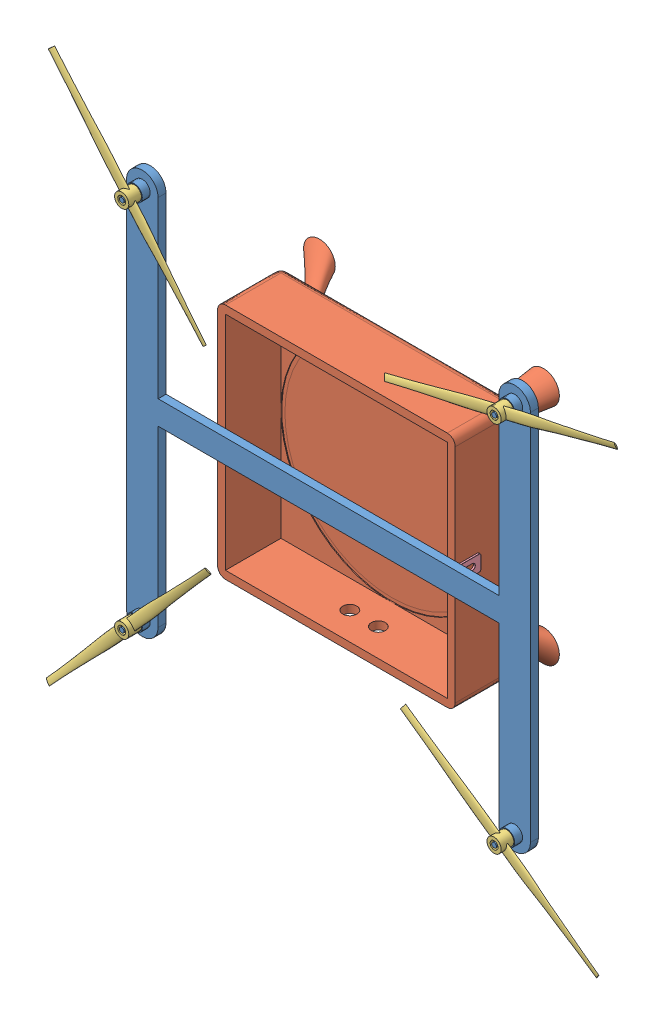
SolidWorks assembly Assembly2, configuration Default. Lengths in mm.
Overall size (362.76 353.79 78).
8 component instances, 4 part files, 19 mates.
Components (placement in the parent):
- arm2-1: arm2 [Default] at (-180.7832 0 40) size (255 255 18)
- body2-1: body2 [Default] at (-180.7832 0 0) x (0 1 0) z (0 0 1) size (161.43 161.43 60)
- blade-1: blade [Default] at (-63.2832 -117.5 50) x (-0.574324 -0.818628 0) z (0 0 1) size (9 150.02 8)
- blade-2: blade [Default] at (-298.2832 -117.5 50) x (0.739775 -0.672854 0) z (0 0 1) size (9 150.02 8)
- blade-3: blade [Default] at (-63.2832 117.5 50) x (0.235026 -0.971989 0) z (0 0 1) size (9 150.02 8)
- blade-4: blade [Default] at (-298.2832 117.5 50) x (0.764856 0.644202 0) z (0 0 1) size (9 150.02 8)
- angle_bracket_15x15x10-3: angle_bracket_15x15x10 [Default] at (-255.7832 -5 40) x (0 0 -1) z (0 1 0) size (15 15 10)
- angle_bracket_15x15x10-4: angle_bracket_15x15x10 [Default] at (-105.7832 5 40) x (0 0 -1) z (0 -1 0) size (15 15 10)
Mates (geometry in assembly coordinates):
- Concentric1: concentric aligned: cylinder of arm2-1 through (-298.2832 117.5 58) axis (0 0 -1) radius 1.5; cylinder of blade-4 through (-298.2832 117.5 58) axis (0 0 -1) radius 2.5
- Coincident5: coincident anti-aligned: plane of arm2-1 through (-298.2832 117.5 50) normal (0 0 1); plane of blade-4 through (-298.2832 117.5 50) normal (0 0 -1)
- Concentric2: concentric aligned: cylinder of arm2-1 through (-63.2832 117.5 58) axis (0 0 -1) radius 1.5; cylinder of blade-3 through (-63.2832 117.5 58) axis (0 0 -1) radius 2.5
- Coincident6: coincident anti-aligned: plane of arm2-1 through (-63.2832 117.5 50) normal (0 0 1); plane of blade-3 through (-63.2832 117.5 50) normal (0 0 -1)
- Concentric3: concentric aligned: cylinder of arm2-1 through (-298.2832 -117.5 58) axis (0 0 -1) radius 1.5; cylinder of blade-2 through (-298.2832 -117.5 58) axis (0 0 -1) radius 2.5
- Coincident7: coincident anti-aligned: plane of arm2-1 through (-298.2832 -117.5 50) normal (0 0 1); plane of blade-2 through (-298.2832 -117.5 50) normal (0 0 -1)
- Concentric5: concentric aligned: cylinder of arm2-1 through (-63.2832 -117.5 58) axis (0 0 -1) radius 1.5; cylinder of blade-1 through (-63.2832 -117.5 58) axis (0 0 -1) radius 2.5
- Coincident8: coincident anti-aligned: plane of arm2-1 through (-63.2832 -117.5 50) normal (0 0 1); plane of blade-1 through (-63.2832 -117.5 50) normal (0 0 -1)
- Coincident24: coincident: point of arm2-1; point of body2-1
- Coincident42: coincident anti-aligned: plane of body2-1 through (-180.7832 0 0) normal (0 0 -1)
- Coincident43: coincident: line of body2-1 through (-258.9452 0 0) axis (1 0 0)
- Parallel11: parallel aligned: line of arm2-1 through (-298.2832 0 40) axis (1 0 0); line of body2-1 through (-258.9452 0 0) axis (1 0 0)
- Coincident46: coincident anti-aligned: plane of arm2-1 through (-298.2832 117.5 40) normal (0 0 -1); plane of body2-1 through (-180.7832 0 40) normal (0 0 1)
- Coincident47: coincident anti-aligned: plane of body2-1 through (-255.7832 -75 40) normal (-1 0 0); plane of angle_bracket_15x15x10-3 through (-255.7832 5 25) normal (1 0 0)
- Coincident48: coincident anti-aligned: plane of arm2-1 through (-298.2832 117.5 40) normal (0 0 -1); plane of angle_bracket_15x15x10-3 through (-255.7832 5 40) normal (0 0 1)
- Coincident49: coincident: line of angle_bracket_15x15x10-3 through (-257.9832 0 38.8) axis (-1 0 0)
- Coincident50: coincident anti-aligned: plane of body2-1 through (-105.7832 -75 40) normal (1 0 0); plane of angle_bracket_15x15x10-4 through (-105.7832 -5 25) normal (-1 0 0)
- Coincident51: coincident anti-aligned: plane of arm2-1 through (-298.2832 117.5 40) normal (0 0 -1); plane of angle_bracket_15x15x10-4 through (-105.7832 -5 40) normal (0 0 1)
- Coincident52: coincident: line of angle_bracket_15x15x10-4 through (-103.5832 0 38.8) axis (1 0 0)
